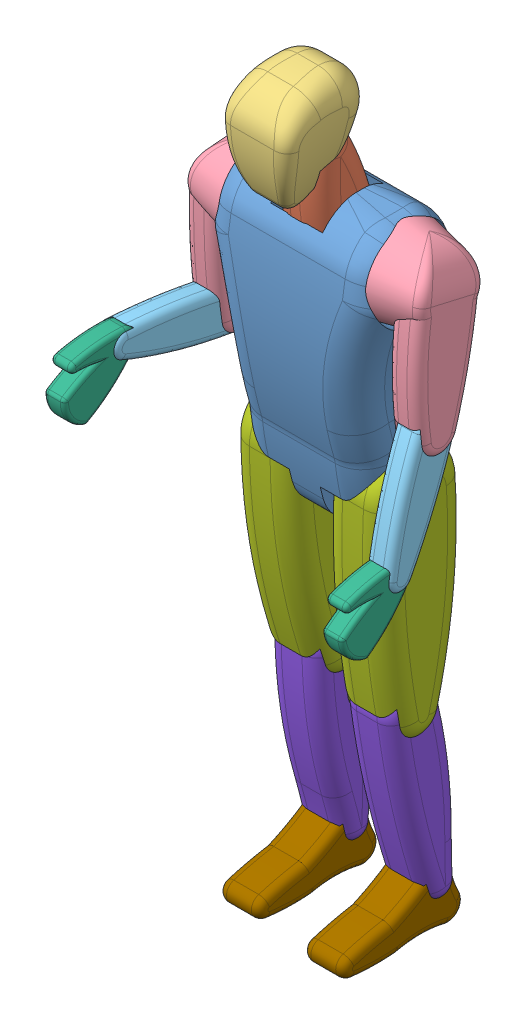
SolidWorks assembly Gubbe, configuration Default. Lengths in mm.
Overall size (587.24 1873.27 705.92).
15 component instances, 9 part files, 0 mates.
Components (placement in the parent):
- Kropp-1: Kropp [Default] at origin size (422.35 716.3 261.74)
- Nacke-1: Nacke [Default] at (0 35.3329 -19.9933) x (-1 0 0) z (0 0.096272 -0.995355) size (127 303.69 155.57)
- Huvud-1: Huvud [Default] at (0 21.1804 -8.1657) x (1 0 0) z (0 -0.24144 0.970416) size (171.5 248.6 227.81)
- ╓verarm-1: ╓verarm [Default] at (-0.1 6.308 43.3285) x (1 0 0) z (0 0.225574 0.974226) size (128.62 422.65 206.39)
- Underarm-1: Underarm [Default] at (-0.1 6.7457 41.2554) x (1 0 0) z (0 0.247545 0.968876) size (63.5 357.53 110.91)
- Hand-1: Hand [Default] at (0 -78.6556 -130.4075) x (1 0 0) z (0 0.705847 0.708365) size (59.04 197.95 139.28)
- ╓verarm-2: ╓verarm [Default] at (0.1 1.2653 -28.7752) x (-1 0 0) z (0 0.087771 -0.996141) size (128.62 422.65 206.39)
- Underarm-2: Underarm [Default] at (0.1 -149.3319 -65.3233) x (-1 0 0) z (0 -0.958616 0.284703) size (63.5 357.53 110.91)
- Hand-2: Hand [Default] at (-508 215.8852 6.0884) x (1 0 0) z (0 0.780776 0.624811) size (59.04 197.95 139.28)
- Lσr-1: Lσr [Default] at (-0.1 -7.673 38.9425) x (1 0 0) z (0 -0.129639 0.991561) size (152.4 600.65 232.31)
- Smalben-1: Smalben [Default] at (-0.1 -4.0676 -28.86) x (1 0 0) z (0 -0.040163 0.999193) size (127 495.02 154.58)
- Fot-1: Fot [Default] at (0.1 -2.0916 -75.3882) size (103.89 141.47 296.74)
- Lσr-2: Lσr [Default] at (0.1 -2.4746 -94.702) x (-1 0 0) z (0 -0.052226 -0.998635) size (152.4 600.65 232.31)
- Smalben-2: Smalben [Default] at (0.1 -28.861 119.2107) x (-1 0 0) z (0 0.231662 -0.972796) size (127 495.02 154.58)
- Fot-2: Fot [Default] at (-228.7 -3.1616 -107.6818) x (1 0 0) z (0 0.008213 0.999966) size (103.89 141.47 296.74)
